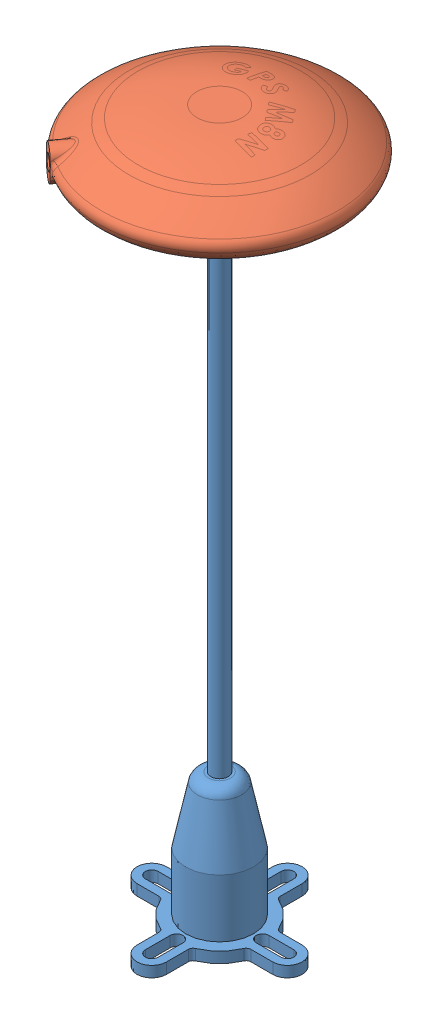
SolidWorks assembly GPS_MN8_ASM, configuration Varsayılan. Lengths in mm.
Overall size (75.6 157.43 75.67).
2 component instances, 2 part files, 2 mates.
Components (placement in the parent):
- GPS MODÜLÜ İSKELETİ-1: GPS MODÜLÜ İSKELETİ [Varsayılan] at (-10.1619 -63.6098 0) size (36.5 144.9 36.5)
- GPS M8N-1: GPS M8N [Varsayılan] at (-10.1619 81.2902 0) x (0.794386 0 0.607413) z (-0.607413 0 0.794386) size (53.76 12.58 54.15)
Mates (geometry in assembly coordinates):
- Eş Merkezli1: concentric anti-aligned: cylinder of GPS MODÜLÜ İSKELETİ-1 through (-10.1619 79.7902 0) axis (0 1 0) radius 17.5; cylinder of GPS M8N-1 through (-10.1619 83.2902 0) axis (0 -1 0) radius 10
- Çakışık1: coincident anti-aligned: plane of GPS MODÜLÜ İSKELETİ-1 through (-10.1619 81.2902 -17.5) normal (0 1 0); plane of GPS M8N-1 through (-10.1619 81.2902 0) normal (0 -1 0)
